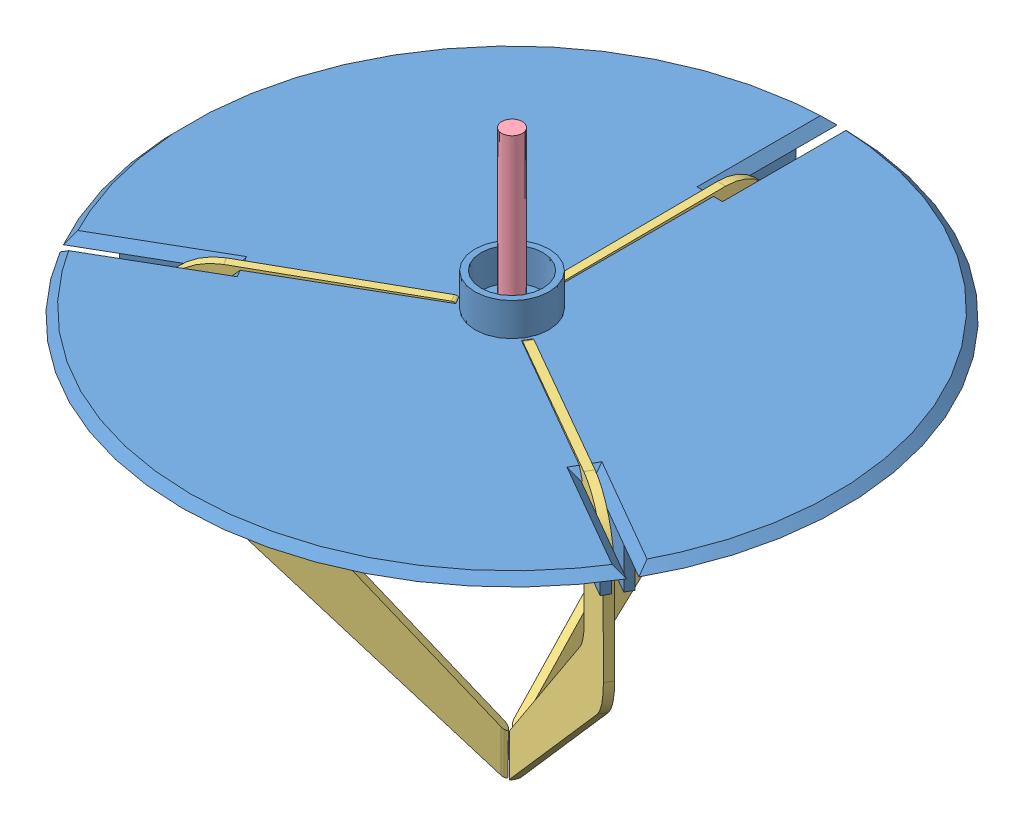
SolidWorks assembly gripping arm, configuration Default. Lengths in mm.
Overall size (160 136.6 159.99).
6 component instances, 4 part files, 8 mates.
Components (placement in the parent):
- holder-1: holder [Default] at (57.5052 102.868 110.8238) size (160 20 159.99)
- pneumatic to arm-1: pneumatic to arm [Default] at (57.5052 102.6344 110.8238) x (0.999262 0 -0.038423) z (-0.038423 0 -0.999262) size (54.95 10 48.9)
- finger-1: finger [Default] at (49.5328 55.8202 116.6969) x (-0.866 0.007662 0.499985) z (-0.006635 -0.999971 0.003831) size (63.72 2 98.85)
- rod-1: rod [Default] at (57.5052 92.9048 110.8238) x (0.882577 0 0.470169) z (-0.470169 0 0.882577) size (5 50 5)
- finger-2: finger [Default] at (56.4052 55.8202 100.983) x (0 0.007662 -0.999971) z (0 -0.999971 -0.007662) size (63.72 2 98.85)
- finger-3: finger [Default] at (66.5776 55.8202 114.7916) x (0.866 0.007662 0.499985) z (0.006635 -0.999971 0.003831) size (63.72 2 98.85)
Mates (geometry in assembly coordinates):
- Parallel2: parallel: plane of holder-1 through (60.6052 92.868 60.8238) normal (1 0 0); plane of pneumatic to arm-1
- Concentric6: concentric aligned: circle of holder-1; circle of rod-1
- Concentric7: concentric anti-aligned: circle of holder-1; circle of pneumatic to arm-1
- Parallel7: parallel aligned: plane of holder-1 through (99.2565 92.868 138.5085) normal (-0.5 0 0.866025); plane of pneumatic to arm-1 through (64.2154 92.6344 118.2382) normal (-0.5 0 0.866025)
- Lock2: lock: unknown of pneumatic to arm-1; unknown of rod-1
- Coincident11: coincident anti-aligned: circle of holder-1; circle of finger-1
- Tangent2: tangent anti-aligned: cylinder of pneumatic to arm-1 through (39.7387 97.6344 129.0881) axis (-0.5 0 -0.866025) radius 2; plane of finger-1 through (35.8328 99.6344 122.2972) normal (-0.006635 -0.999971 0.003831)
- PathMate2: path: point of pneumatic to arm-1; line of assembly
